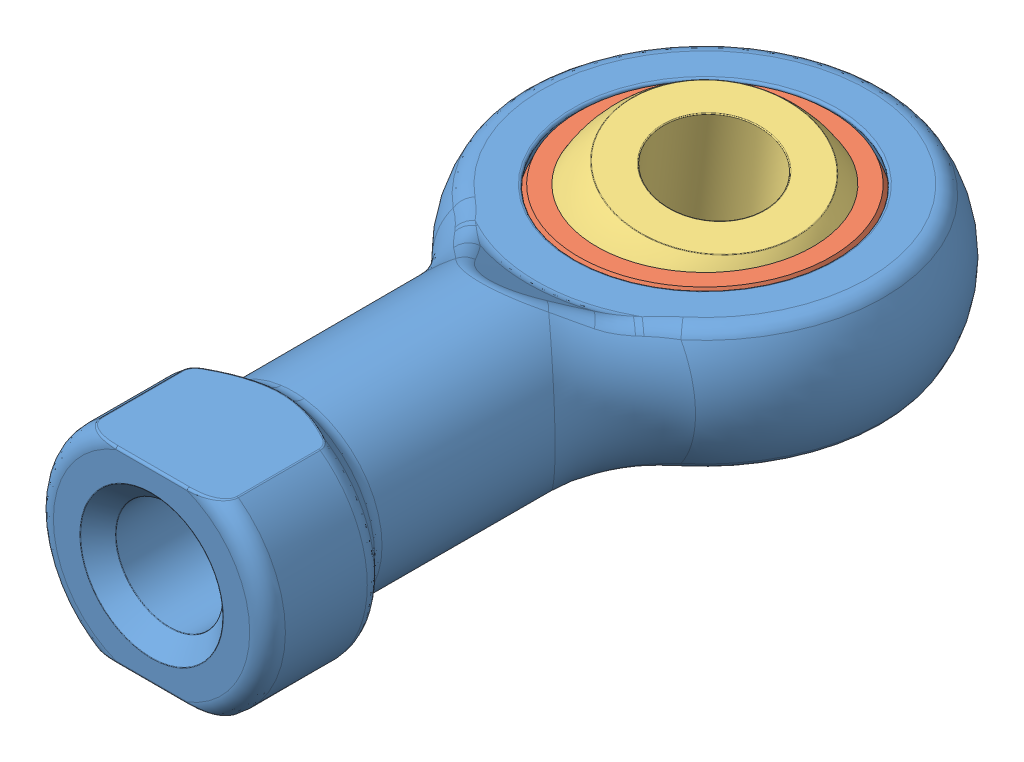
SolidWorks assembly BallJoint Assy, configuration Default. Lengths in mm.
Overall size (10.82 6.52 21).
3 component instances, 3 part files, 4 mates.
Components (placement in the parent):
- Body-1: Body [Default] at origin size (10.82 5.6 21)
- Liner-1: Liner [Default] at (0 0 18.0928) x (0.47258 0 0.881288) z (-0.881288 0 0.47258) size (7.88 3.5 7.88)
- Ball-1: Ball [Default] at (0 0 18.0928) x (0.766515 -0.174296 0.618122) z (-0.619213 0.054765 0.783311) size (7 5 7)
Mates (geometry in assembly coordinates):
- Concentric1: concentric: sphere of Body-1; sphere of Liner-1
- Coincident1: coincident aligned: plane of Liner-1 through (0 0 18.0928) normal (0 1 0); plane of assembly through (0 0 0) normal (0 1 0)
- Concentric2: concentric: sphere of Liner-1; sphere of Ball-1
- LimitAngle1: limit planar angle = 0.183729 rad aligned: plane of Ball-1 through (1.5757 2.1965 19.1849) normal (0.170379 0.983169 0.065948); plane of Liner-1 through (1.4324 1.75 20.7641) normal (0 1 0)
